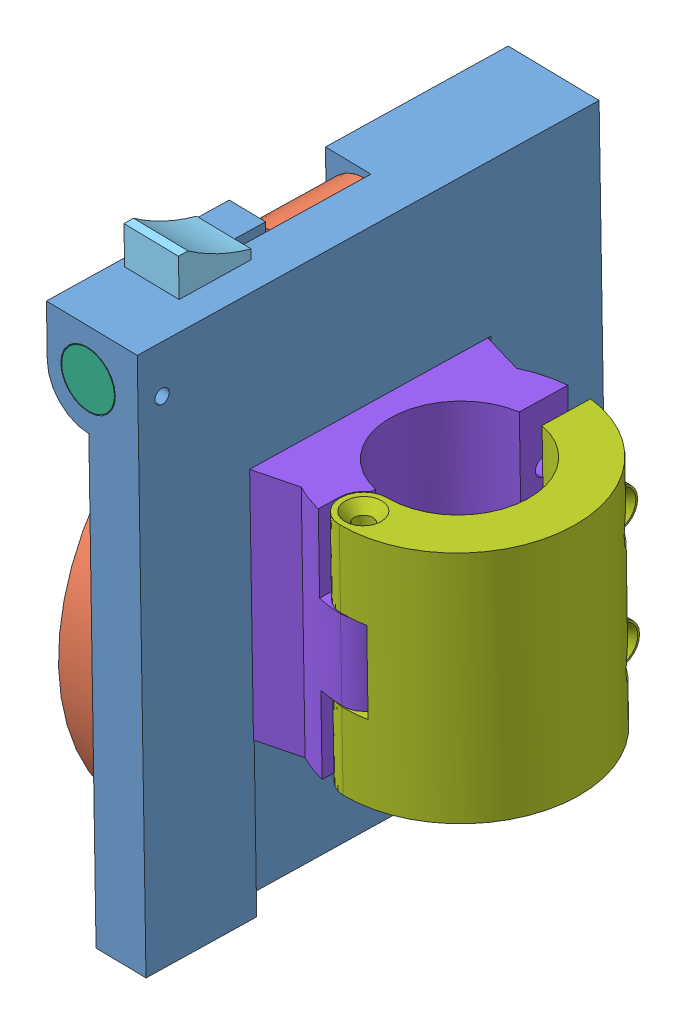
SolidWorks assembly Cupholder, configuration Default. Lengths in mm.
Overall size (67.9 124.38 97.21).
8 component instances, 8 part files, 14 mates.
Components (placement in the parent):
- backplate-1: backplate [Default] at (-175.5905 23.1855 -60.3337) x (-0.028692 -0.006205 0.999569) z (0.999535 0.010173 0.028754) size (96 115 20)
- Cupholder-1: Cupholder [Default] at (-186.5854 23.0736 -60.65) x (-0.010347 0.999929 0.00591) z (0.028692 0.006205 -0.999569) size (113.05 17.6 93.5)
- endcap-1: endcap [Default] at (-186.5107 23.1373 -71.2988) x (-0.490806 -0.871051 -0.019495) z (0.028692 0.006205 -0.999569) size (11.09 9.6 9.6)
- mid piece-2: mid piece [Default] at (-187.0845 23.0132 -51.3074) x (-0.490806 -0.871051 -0.019495) z (0.028692 0.006205 -0.999569) size (11.09 9.6 20)
- locking piece-1: locking piece [Default] at (-187.6584 22.8891 -31.316) x (-0.999535 -0.010173 -0.028754) z (0.010347 -0.999929 -0.00591) size (12 25 23.8)
- spring holder-1: spring holder [Default] at (-187.9626 22.7758 -12.6707) x (-0.999535 -0.010173 -0.028754) z (-0.028692 -0.006205 0.999569) size (11.6 11.6 18)
- Mount_Ver2-1: Mount_Ver2 [Default] at (-155.381 1.1381 -59.4903) x (-0.999535 -0.010173 -0.028754) z (0.010347 -0.999929 -0.00591) size (30 49.87 50)
- Mount_Ver2_Second_Half_2-1: Mount_Ver2_Second_Half_2 [Default] at (-155.381 1.1381 -59.4903) x (-0.999535 -0.010173 -0.028754) z (0.010347 -0.999929 -0.00591) size (30 59.2 50)
Mates (geometry in assembly coordinates):
- Concentric3: concentric anti-aligned: circle of mid piece^Assem2-2; circle of locking piece^Assem2-1
- Concentric4: concentric aligned: circle of endcap^Assem2-1; circle of mid piece^Assem2-2
- Coincident6: coincident anti-aligned: plane of endcap^Assem2-1 through (-186.5107 23.1373 -71.2988) normal (-0.028692 -0.006205 0.999569); plane of mid piece^Assem2-2 through (-186.5107 23.1373 -71.2988) normal (0.028692 0.006205 -0.999569)
- Coincident7: coincident anti-aligned: plane of mid piece^Assem2-2 through (-187.0845 23.0132 -51.3074) normal (-0.028692 -0.006205 0.999569); plane of locking piece^Assem2-1 through (-187.0845 23.0132 -51.3074) normal (0.028692 0.006205 -0.999569)
- Coincident21: coincident anti-aligned: plane of Copy of backplate^Assem2-1 through (-193.2169 22.8287 -30.829) normal (0.870796 -0.491154 0.021947); plane of locking piece^Assem2-1 through (-192.6245 22.9568 -51.4667) normal (-0.870796 0.491154 -0.021947)
- Coincident22: coincident anti-aligned: plane of Copy of backplate^Assem2-1 through (-190.2798 17.8584 -30.7755) normal (0.860449 0.508775 0.027857); plane of locking piece^Assem2-1 through (-189.8049 18.1854 -51.4154) normal (-0.860449 -0.508775 -0.027857)
- Coincident26: coincident aligned: plane of Copy of backplate^Assem2-1 through (-176.8642 12.8884 -12.4135) normal (-0.028692 -0.006205 0.999569); plane of Part1^Assem2-1 through (-187.9626 22.7758 -12.6707) normal (-0.028692 -0.006205 0.999569)
- Concentric10: concentric aligned: cylinder of Copy of Mount_Ver2^Assem2-1 through (-155.4375 -48.9825 -39.7944) axis (-0.010347 0.999929 0.00591) radius 5; cylinder of Copy of Mount_Ver2_Second_Half_2^Assem2-1 through (-155.7841 -15.4849 -39.5965) axis (-0.010347 0.999929 0.00591) radius 5.2
- Coincident34: coincident aligned: plane of Copy of Mount_Ver2^Assem2-1 through (-155.381 1.1381 -59.4903) normal (-0.010347 0.999929 0.00591); plane of Copy of Mount_Ver2_Second_Half_2^Assem2-1 through (-155.381 1.1381 -59.4903) normal (-0.010347 0.999929 0.00591)
- Concentric11: concentric aligned: cylinder of Copy of backplate^Assem2-1 through (-186.8723 23.0116 -50.6543) axis (0.028692 0.006205 -0.999569) radius 9; cylinder of Cupholder^Assem2-1 through (-186.8665 23.0128 -50.8542) axis (0.028692 0.006205 -0.999569) radius 8.8
- Distance1: distance = 0.2 mm anti-aligned: plane of Cupholder^Assem2-1 through (-195.5405 11.1354 -51.177) normal (-0.028692 -0.006205 0.999569); plane of Copy of backplate^Assem2-1 through (-195.7646 12.9207 -50.9722) normal (0.028692 0.006205 -0.999569)
- Concentric13: concentric anti-aligned: cylinder of Copy of backplate^Assem2-1 through (-187.9626 22.7758 -12.6707) axis (0.028692 0.006205 -0.999569) radius 6; cylinder of Part1^Assem2-1 through (-187.4461 22.8875 -30.663) axis (-0.028692 -0.006205 0.999569) radius 5.8
- Coincident41: coincident anti-aligned: plane of Copy of backplate^Assem2-1 through (-175.3602 0.9371 -60.4652) normal (0.010347 -0.999929 -0.00591); plane of Copy of Mount_Ver2_Second_Half_2^Assem2-1 through (-155.381 1.1381 -59.4903) normal (-0.010347 0.999929 0.00591)
- Coincident42: coincident anti-aligned: plane of Copy of backplate^Assem2-1 through (-179.4972 1.0724 -90.5961) normal (0.999535 0.010173 0.028754); plane of Copy of Mount_Ver2_Second_Half_2^Assem2-1 through (-178.3737 -109.723 -90.4512) normal (-0.999535 -0.010173 -0.028754)
